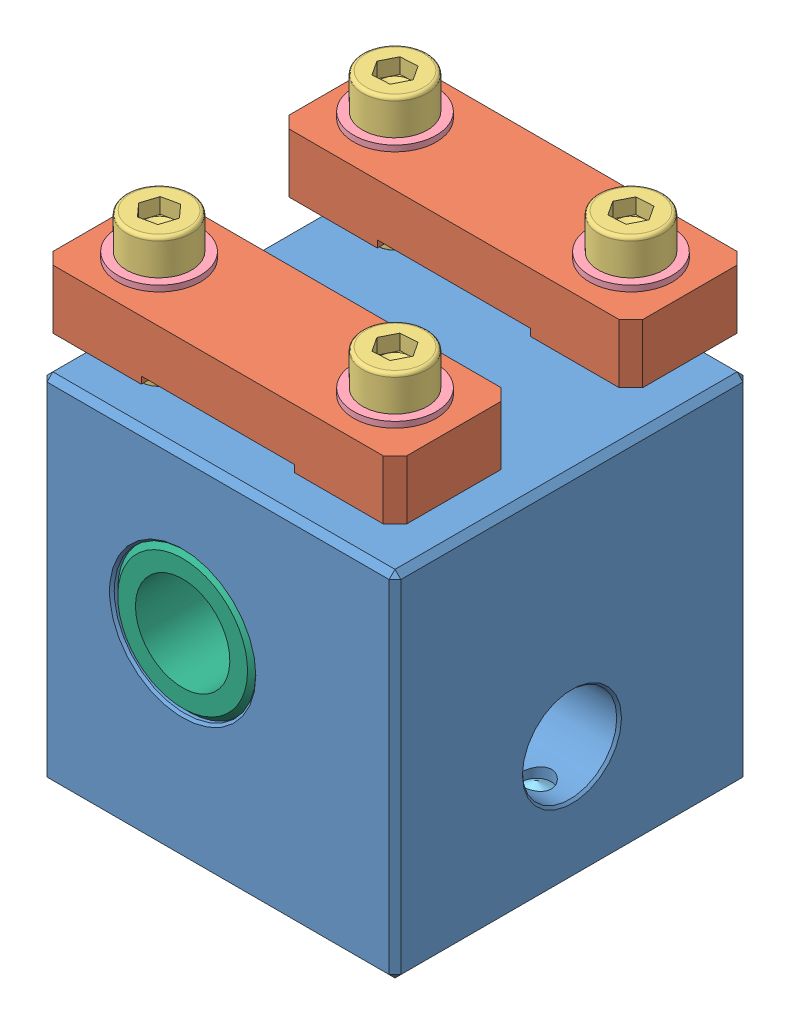
SolidWorks assembly Slider, configuration Default. Lengths in mm.
Overall size (30 42.12 30).
14 component instances, 6 part files, 27 mates.
Components (placement in the parent):
- cubic slider-1: cubic slider [Default] at origin size (30 30 30)
- belt clamp (aluminum)-1: belt clamp (aluminum) [Default] at (15 33.3347 25) x (1 0 0) z (0 -1 0) size (30 10 5)
- belt clamp (aluminum)-2: belt clamp (aluminum) [Default] at (15 33.3347 5) x (1 0 0) z (0 -1 0) size (30 10 5)
- Socket head cap screw-13: Socket head cap screw [M3x14] at (25 41.8347 25) x (0 -1 0) z (0.893569 0 0.448926) size (17 5.5 5.5)
- Plain washer-1: Plain washer [M3 plain washer] at (25 38.8347 25) x (0 1 0) z (-0.184757 0 0.982784) size (0.5 7 7)
- Plain washer-2: Plain washer [M3 plain washer] at (5 38.8347 25) x (0 1 0) z (-0.184757 0 0.982784) size (0.5 7 7)
- Socket head cap screw-10: Socket head cap screw [M3x14] at (5 41.8347 25) x (0 -1 0) z (0.211245 0 0.977433) size (17 5.5 5.5)
- Socket head cap screw-11: Socket head cap screw [M3x14] at (5 42.1176 5) x (0 -1 0) z (0.893569 0 0.448926) size (17 5.5 5.5)
- Plain washer-3: Plain washer [M3 plain washer] at (5 39.1176 5) x (0 1 0) z (0.413277 0 0.910606) size (0.5 7 7)
- Socket head cap screw-12: Socket head cap screw [M3x14] at (25 41.8347 5) x (0 -1 0) z (0.893569 0 0.448926) size (17 5.5 5.5)
- Plain washer-4: Plain washer [M3 plain washer] at (25 38.8347 5) x (0 1 0) z (-0.184757 0 0.982784) size (0.5 7 7)
- hex grub screw-1: hex grub screw [M3x6] at (27 0 15) x (0 1 0) z (0.563835 0 -0.825888) size (6 3 3)
- 8x12x15mm Bronze bushing-1: 8x12x15mm Bronze bushing [Default] at (12 16.8 15) x (0.999738 -0.022894 0) z (0 0 1) size (12 12 15)
- 8x12x15mm Bronze bushing-2: 8x12x15mm Bronze bushing [Default] at (12 16.8 0) size (12 12 15)
Mates (geometry in assembly coordinates):
- Coincident2: coincident aligned: plane of cubic slider-1 through (30 0 30) normal (1 0 0); plane of belt clamp (aluminum)-1 through (30 38.3347 20) normal (1 0 0)
- Coincident3: coincident aligned: plane of cubic slider-1 through (30 0 30) normal (1 0 0); plane of belt clamp (aluminum)-1 through (30 38.3347 20) normal (1 0 0)
- Coincident4: coincident aligned: plane of cubic slider-1 through (0 0 30) normal (0 0 1); plane of belt clamp (aluminum)-1 through (30 38.3347 30) normal (0 0 1)
- Coincident5: coincident aligned: plane of cubic slider-1 through (0 0 0) normal (0 0 -1); plane of belt clamp (aluminum)-2 through (31.4091 38.3347 0) normal (0 0 -1)
- Concentric2: concentric aligned: circle of cubic slider-1; cylinder of Socket head cap screw-13 through (25 73.5847 25) axis (0 1 0) radius 1.5
- Concentric3: concentric anti-aligned: cylinder of Socket head cap screw-13 through (25 73.5847 25) axis (0 1 0) radius 1.5; circle of Plain washer-1
- Coincident8: coincident anti-aligned: plane of Socket head cap screw-13 through (26.2345 38.8347 22.5427) normal (0 -1 0); plane of Plain washer-1 through (23.4275 38.8347 24.7044) normal (0 1 0)
- Coincident9: coincident anti-aligned: plane of belt clamp (aluminum)-1 through (15 38.3347 25) normal (0 1 0); plane of Plain washer-1 through (21.5603 38.3347 24.3534) normal (0 -1 0)
- Concentric4: concentric anti-aligned: circle of Plain washer-2; cylinder of Socket head cap screw-10 through (5 73.5847 25) axis (0 1 0) radius 1.5
- Coincident10: coincident anti-aligned: plane of Plain washer-2 through (3.4275 38.8347 24.7044) normal (0 1 0); plane of Socket head cap screw-10 through (7.6879 38.8347 24.4191) normal (0 -1 0)
- Concentric5: concentric aligned: cylinder of cubic slider-1 through (5 30 25) axis (0 1 0) radius 1.25; cylinder of Socket head cap screw-10 through (5 73.5847 25) axis (0 1 0) radius 1.5
- Coincident11: coincident anti-aligned: plane of belt clamp (aluminum)-1 through (15 38.3347 25) normal (0 1 0); plane of Plain washer-2 through (1.5603 38.3347 24.3534) normal (0 -1 0)
- Concentric6: concentric anti-aligned: cylinder of Socket head cap screw-11 through (5 73.8676 5) axis (0 1 0) radius 1.5; circle of Plain washer-3
- Coincident12: coincident anti-aligned: plane of Socket head cap screw-11 through (6.2345 39.1176 2.5427) normal (0 -1 0); plane of Plain washer-3 through (3.543 39.1176 5.6612) normal (0 1 0)
- Concentric7: concentric aligned: cylinder of cubic slider-1 through (5 30 5) axis (0 1 0) radius 1.25; cylinder of Socket head cap screw-11 through (5 73.8676 5) axis (0 1 0) radius 1.5
- Concentric8: concentric anti-aligned: cylinder of Socket head cap screw-12 through (25 73.5847 5) axis (0 1 0) radius 1.5; circle of Plain washer-4
- Coincident14: coincident anti-aligned: plane of Socket head cap screw-12 through (26.2345 38.8347 2.5427) normal (0 -1 0); plane of Plain washer-4 through (23.4275 38.8347 4.7044) normal (0 1 0)
- Concentric9: concentric aligned: cylinder of cubic slider-1 through (25 30 5) axis (0 1 0) radius 1.25; cylinder of Socket head cap screw-12 through (25 73.5847 5) axis (0 1 0) radius 1.5
- Concentric10: concentric aligned: cylinder of cubic slider-1 through (27 0 15) axis (0 -1 0) radius 1.25; cylinder of hex grub screw-1 through (27 -12.7 15) axis (0 -1 0) radius 1.5
- Coincident16: coincident aligned: plane of cubic slider-1 through (0 0 30) normal (0 -1 0); plane of hex grub screw-1 through (27 0 15) normal (0 -1 0)
- Concentric11: concentric aligned: cylinder of cubic slider-1 through (12 16.8 30) axis (0 0 -1) radius 6; cylinder of 8x12x15mm Bronze bushing-2 through (12 16.8 15) axis (0 0 -1) radius 6
- Coincident17: coincident aligned: plane of cubic slider-1 through (0 0 0) normal (0 0 -1); plane of 8x12x15mm Bronze bushing-2 through (12 16.8 0) normal (0 0 -1)
- Concentric12: concentric aligned: cylinder of cubic slider-1 through (12 16.8 30) axis (0 0 -1) radius 6; cylinder of 8x12x15mm Bronze bushing-1 through (12 16.8 30) axis (0 0 -1) radius 6
- Coincident18: coincident aligned: plane of cubic slider-1 through (0 0 30) normal (0 0 1); plane of 8x12x15mm Bronze bushing-1 through (12 16.8 30) normal (0 0 1)
- Coincident19: coincident aligned: plane of belt clamp (aluminum)-1 through (15 38.3347 25) normal (0 1 0); plane of belt clamp (aluminum)-2 through (16.4091 38.3347 5) normal (0 1 0)
- Coincident20: coincident anti-aligned: plane of belt clamp (aluminum)-2 through (16.4091 38.3347 5) normal (0 1 0); circle of Plain washer-4
- Coincident21: coincident aligned: plane of belt clamp (aluminum)-1 through (30 38.3347 20) normal (1 0 0); plane of belt clamp (aluminum)-2 through (30 38.3347 0) normal (1 0 0)
